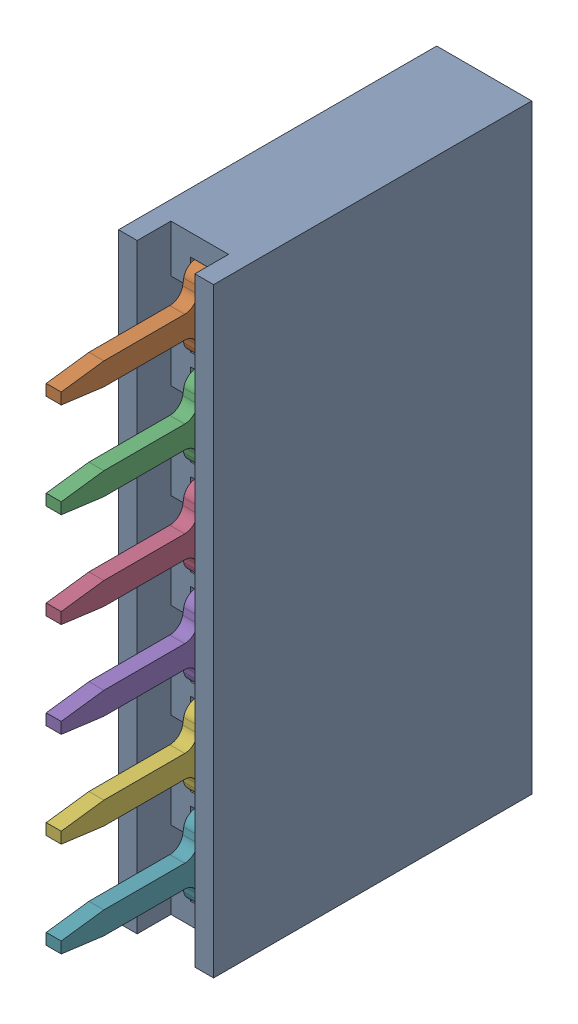
SolidWorks assembly H2_1.step, configuration Default. Lengths in mm.
Overall size (2.54 16.04 11.5).
8 component instances, 2 part files, 0 mates.
Components (placement in the parent):
- DS1023-1x6SF11_1.step-3: DS1023-1x6SF11_1.step [Default] at (501.645 334.5179 -1.647) x (0 -1 0) z (0 0 -1) size (16.04 2.54 11.5)
  - body_3.step-8: body_3.step [Default] at origin size (16.04 2.54 8.5)
  - contact_1.step-51: contact_1.step [Default] at origin size (2.3 0.4 9)
  - contact_1.step-52: contact_1.step [Default] at (2.54 0 0) size (2.3 0.4 9)
  - contact_1.step-55: contact_1.step [Default] at (5.08 0 0) size (2.3 0.4 9)
  - contact_1.step-56: contact_1.step [Default] at (7.62 0 0) size (2.3 0.4 9)
  - contact_1.step-57: contact_1.step [Default] at (10.16 0 0) size (2.3 0.4 9)
  - contact_1.step-58: contact_1.step [Default] at (12.7 0 0) size (2.3 0.4 9)
